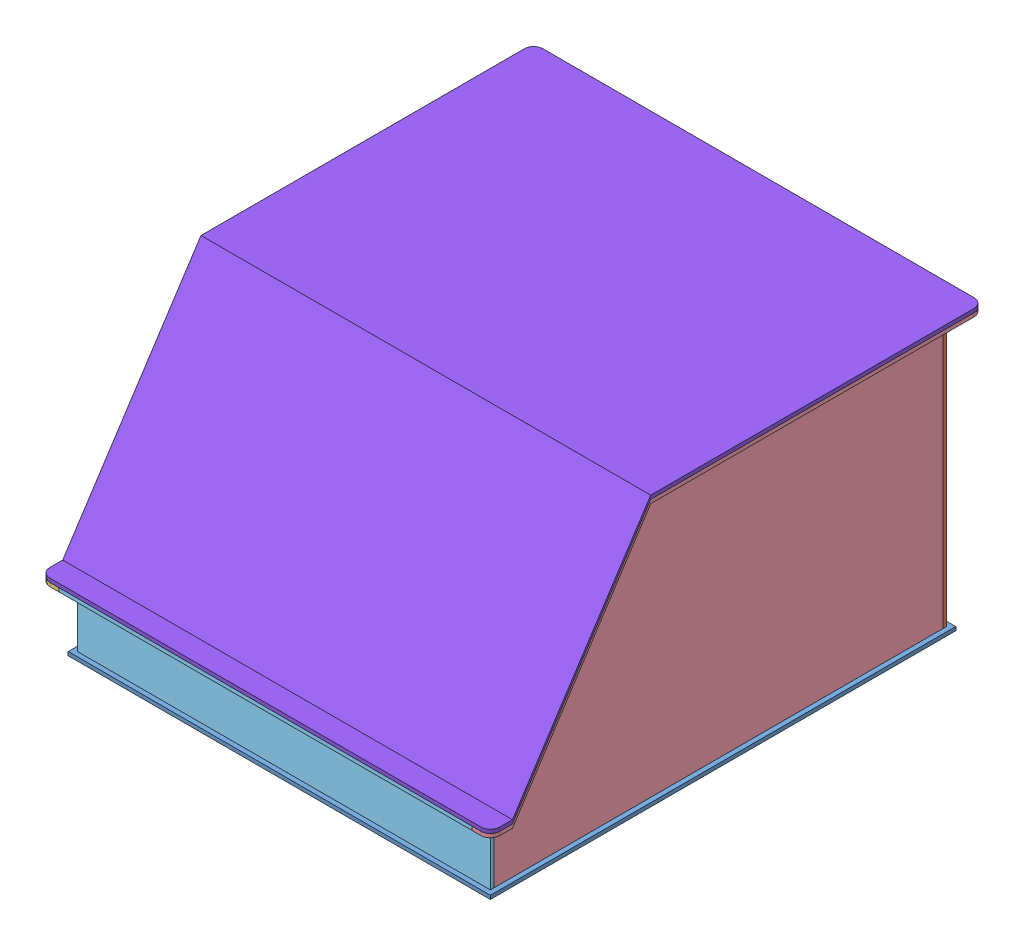
SolidWorks assembly BatteryBoxWithCover, configuration Default. Lengths in mm.
Overall size (488 308 535).
12 component instances, 8 part files, 26 mates.
Components (placement in the parent):
- box_base-1: box_base [Default] at (-41.9141 184.8935 556.0522) size (458 4 505)
- box_back-1: box_back [Default] at (411.0859 188.8935 56.0522) x (-1 0 0) z (0 0 -1) size (448 300 24)
- box_side-1: box_side [Default] at (-32.9141 188.8935 60.0522) x (0 0 1) z (-1 0 0) size (535 300 24)
- box_sidemirrored-2: box_sidemirrored [Default] at (411.0859 188.8935 60.0522) x (0 0 1) z (-1 0 0) size (535 300 24)
- box_front-1: box_front [Default] at (187.0859 188.8935 547.0522) x (-1 0 0) z (0 0 -1) size (448 70 24)
- box_inner-1: box_inner [Default] at (333.0859 188.8935 397.0522) x (0 0 -1) z (1 0 0) size (337 230 4)
- box_inner-2: box_inner [Default] at (259.0859 188.8935 397.0522) x (0 0 -1) z (1 0 0) size (337 230 4)
- box_inner-3: box_inner [Default] at (185.0859 188.8935 397.0522) x (0 0 -1) z (1 0 0) size (337 230 4)
- box_inner-4: box_inner [Default] at (111.0859 188.8935 397.0522) x (0 0 -1) z (1 0 0) size (337 230 4)
- box_inner-5: box_inner [Default] at (37.0859 188.8935 397.0522) x (0 0 -1) z (1 0 0) size (337 230 4)
- box_frontdivider-1: box_frontdivider [Default] at (407.0859 188.8935 401.0522) x (-1 0 0) z (0 0 -1) size (440 250 34)
- box_TopCover-1: box_TopCover [Default] at (431.0859 488.8935 36.0522) x (-1 0 0) z (0 0 -1) size (488 234 535)
Mates (geometry in assembly coordinates):
- Coincident3: coincident aligned: line of box_side-1 through (-36.9141 188.8935 547.0522) axis (0 1 0); line of box_front-1 through (-36.9141 188.8935 547.0522) axis (0 1 0)
- Coincident4: coincident anti-aligned: line of box_sidemirrored-2 through (411.0859 188.8935 547.0522) axis (0 1 0); line of box_front-1 through (411.0859 258.8935 547.0522) axis (0 -1 0)
- Coincident6: coincident aligned: line of box_back-1 through (411.0859 488.8935 60.0522) axis (0 -1 0); line of box_sidemirrored-2 through (411.0859 484.8935 60.0522) axis (0 -1 0)
- Coincident7: coincident anti-aligned: line of box_back-1 through (-36.9141 188.8935 60.0522) axis (0 1 0); line of box_side-1 through (-36.9141 484.8935 60.0522) axis (0 -1 0)
- Coincident9: coincident anti-aligned: line of box_back-1 through (411.0859 188.8935 60.0522) axis (-1 0 0); line of box_sidemirrored-2 through (407.0859 188.8935 60.0522) axis (1 0 0)
- Coincident10: coincident anti-aligned: line of box_side-1 through (-36.9141 188.8935 547.0522) axis (1 0 0); line of box_front-1 through (411.0859 188.8935 547.0522) axis (-1 0 0)
- Coincident23: coincident anti-aligned: line of box_sidemirrored-2 through (411.0859 188.8935 547.0522) axis (0 1 0); line of box_front-1 through (411.0859 258.8935 547.0522) axis (0 -1 0)
- Coincident24: coincident anti-aligned: plane of box_sidemirrored-2 through (407.0859 258.8935 547.0522) normal (0 0 1); plane of box_front-1 through (187.0859 188.8935 547.0522) normal (0 0 -1)
- Coincident25: coincident anti-aligned: line of box_sidemirrored-2 through (407.0859 188.8935 547.0522) axis (1 0 0); line of box_front-1 through (411.0859 188.8935 547.0522) axis (-1 0 0)
- Coincident26: coincident: point of box_base-1; point of box_back-1
- Coincident27: coincident: point of box_base-1; point of box_back-1
- Coincident29: coincident: point of box_base-1; point of box_front-1
- Coincident30: coincident: line of box_inner-5 through (41.0859 188.8935 397.0522) axis (0 0 -1); line of box_base-1 through (41.0859 188.8935 56.0522) axis (0 0 1)
- Coincident31: coincident: line of box_base-1 through (-36.9141 188.8935 397.0522) axis (1 0 0); line of box_inner-5 through (41.0859 188.8935 397.0522) axis (-1 0 0)
- Coincident32: coincident: line of box_inner-4 through (115.0859 188.8935 397.0522) axis (0 0 -1); line of box_base-1 through (115.0859 188.8935 56.0522) axis (0 0 1)
- Coincident33: coincident: line of box_base-1 through (-36.9141 188.8935 397.0522) axis (1 0 0); line of box_inner-4 through (115.0859 188.8935 397.0522) axis (-1 0 0)
- Coincident34: coincident: line of box_base-1 through (-36.9141 188.8935 397.0522) axis (1 0 0); line of box_inner-3 through (189.0859 188.8935 397.0522) axis (-1 0 0)
- Coincident35: coincident: line of box_base-1 through (189.0859 188.8935 56.0522) axis (0 0 1); line of box_inner-3 through (189.0859 188.8935 397.0522) axis (0 0 -1)
- Coincident36: coincident: line of box_base-1 through (-36.9141 188.8935 397.0522) axis (1 0 0); line of box_inner-2 through (263.0859 188.8935 397.0522) axis (-1 0 0)
- Coincident37: coincident: line of box_base-1 through (263.0859 188.8935 56.0522) axis (0 0 1); line of box_inner-2 through (263.0859 188.8935 397.0522) axis (0 0 -1)
- Coincident38: coincident: line of box_base-1 through (-36.9141 188.8935 397.0522) axis (1 0 0); line of box_inner-1 through (337.0859 188.8935 397.0522) axis (-1 0 0)
- Coincident39: coincident: line of box_base-1 through (337.0859 188.8935 56.0522) axis (0 0 1); line of box_inner-1 through (337.0859 188.8935 397.0522) axis (0 0 -1)
- Coincident40: coincident: line of box_base-1 through (-36.9141 188.8935 401.0522) axis (1 0 0); line of box_frontdivider-1 through (407.0859 188.8935 401.0522) axis (-1 0 0)
- Coincident41: coincident aligned: line of box_sidemirrored-2 through (407.0859 188.8935 60.0522) axis (0 0 1); line of box_frontdivider-1 through (407.0859 188.8935 397.0522) axis (0 0 1)
- Coincident42: coincident anti-aligned: line of box_TopCover-1 through (-46.9141 258.8935 571.0522) axis (1 0 0); line of box_front-1 through (411.0859 258.8935 571.0522) axis (-1 0 0)
- Coincident43: coincident aligned: line of box_side-1 through (-56.9141 258.8935 561.0522) axis (0 0 -1); line of box_TopCover-1 through (-56.9141 258.8935 561.0522) axis (0 0 -1)
